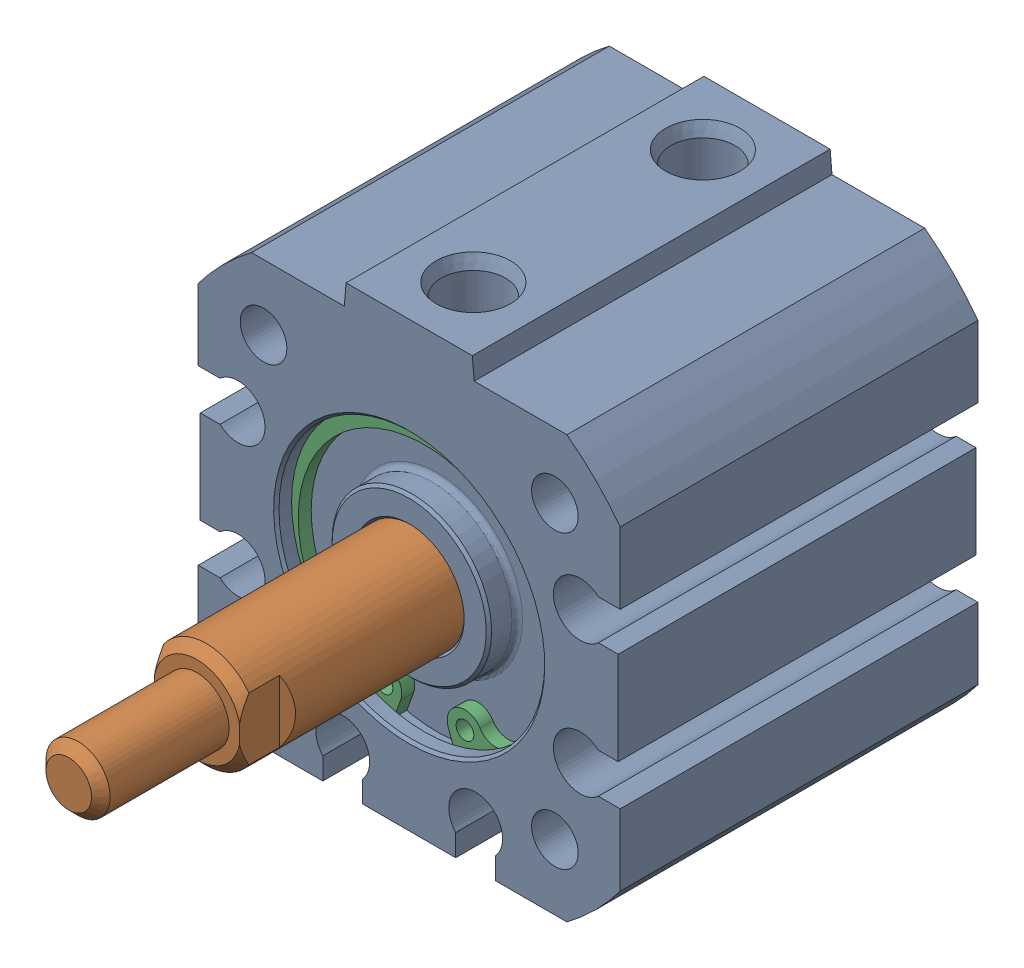
SolidWorks assembly 217-2778-001 Rev2_NCQ8A075-050M, configuration Default. Lengths in mm.
Overall size (31.75 33.34 52.54).
3 component instances, 3 part files, 0 mates.
Components (placement in the parent):
- 217-2778-NCQ8A075-050M_NCQ8 Tube_075A-1: 217-2778-NCQ8A075-050M_NCQ8 Tube_075A [Default] at origin size (31.75 33.34 26.92)
- 217-2778-NCQ8A075-050M_NCQ8 Rod_075M-1: 217-2778-NCQ8A075-050M_NCQ8 Rod_075M [Default] at (0 0 3.8126) x (-1 0 0) z (0 0 1) size (18.95 18.95 35.27)
- 217-2778-NCQ8A075-050M_Snap Ring_075-1: 217-2778-NCQ8A075-050M_Snap Ring_075 [Default] at (0 0 10.362) size (21 20.74 0.97)
